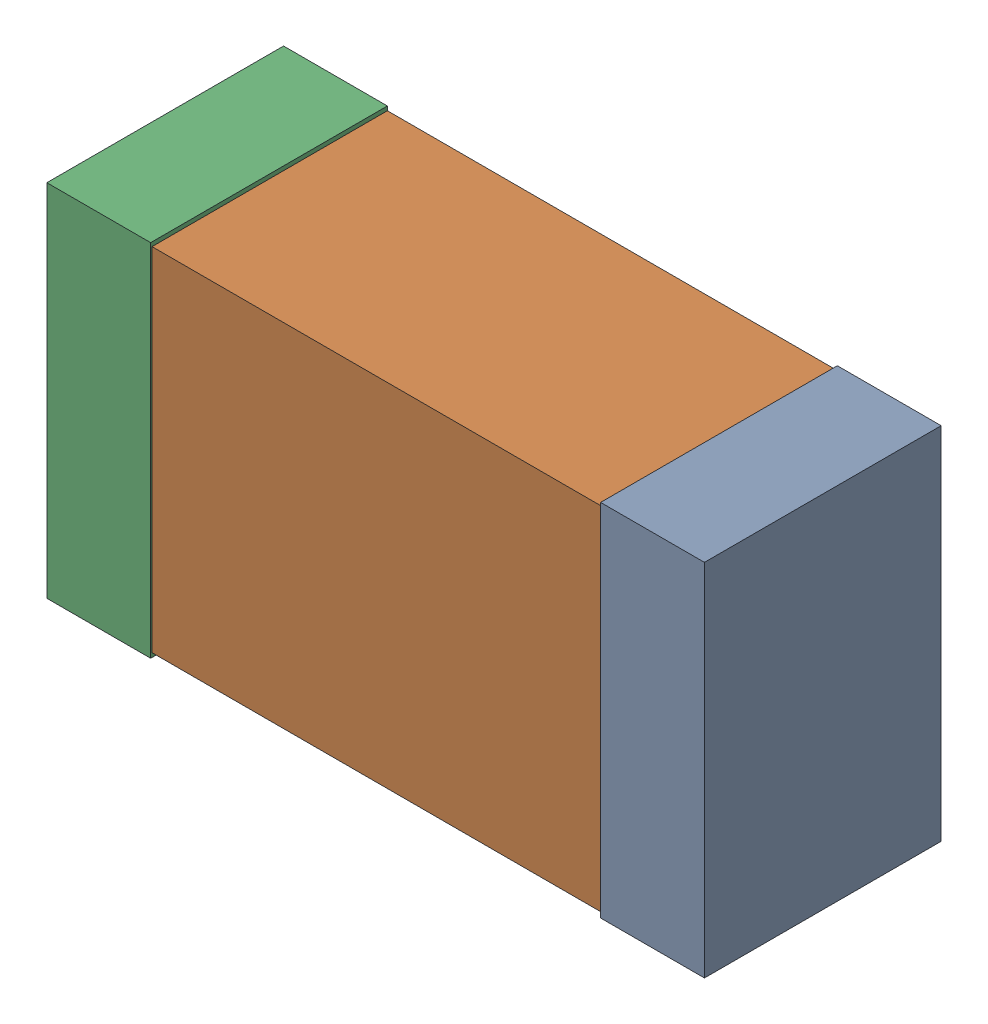
SolidWorks assembly C5Kanaloa_v2.0.0_Power, configuration Default. Lengths in mm.
Overall size (2.38 1.3 0.85).
6 component instances, 2 part files, 0 mates.
Components (placement in the parent):
- 352877648-1: 352877648 [Default] at (74.556 90.678 0) size (0.38 1.3 0.85)
  - Extruded_14-1: Extruded_14 [Default] at origin size (0.38 1.3 0.85)
- 352877904-1: 352877904 [Default] at (73.556 90.678 0) size (2.2 1.27 0.85)
  - Extruded_18-1: Extruded_18 [Default] at origin size (2.2 1.27 0.85)
- 352877648-2: 352877648 [Default] at (72.556 90.678 0) size (0.38 1.3 0.85)
  - Extruded_14-1: Extruded_14 [Default] at origin size (0.38 1.3 0.85)
